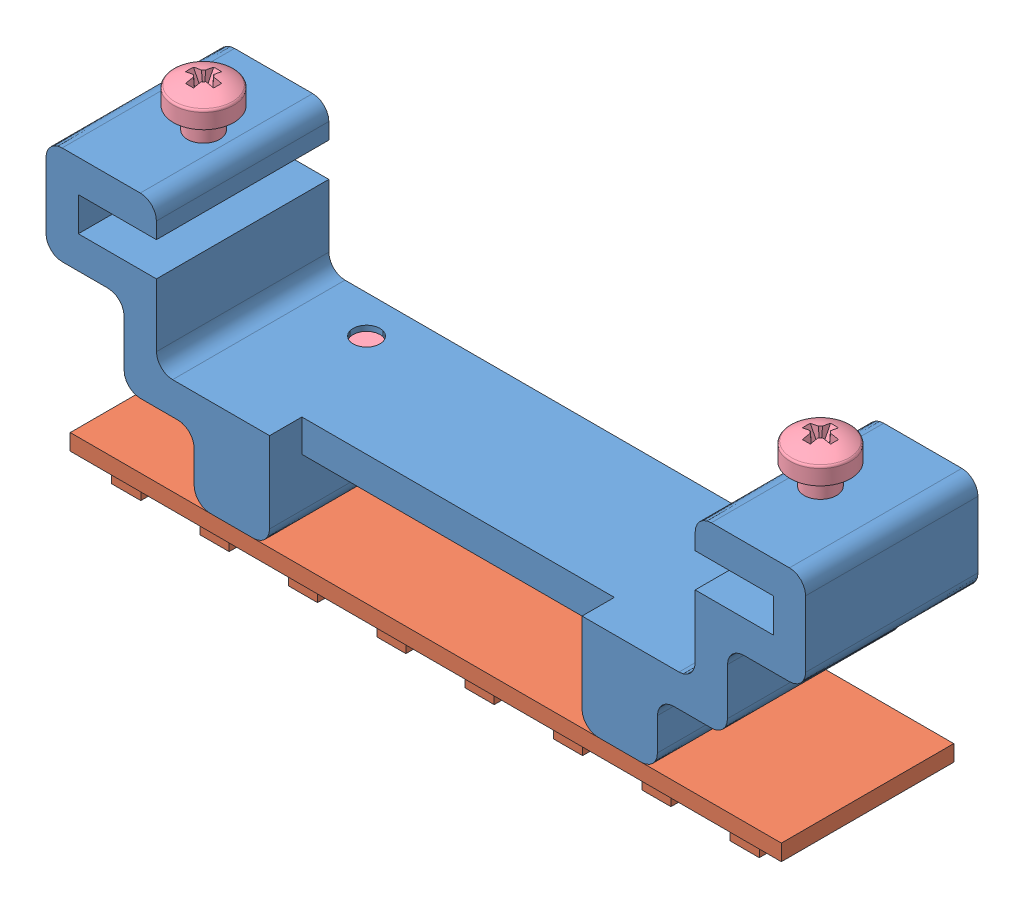
SolidWorks assembly Assembly schuiver QTR-8A, configuration Default. Lengths in mm.
Overall size (70.5 30.71 16).
7 component instances, 4 part files, 23 mates.
Components (placement in the parent):
- QTR-8A schuiver-1: QTR-8A schuiver [Default] at (0 0 -13.425) size (70.5 22.5 16)
- QTR-8A-1: QTR-8A [Default] at (0 -21 -5.425) x (1 0 0) z (0 0 -1) size (66 3.1 16)
- Header11P90-1: Header11P90 [Default] at (-12.7 -22.46 -12.155) x (0 0 1) z (0 1 0) size (8.45 27.94 7.3)
- pan head cross recess screw_iso-1: pan head cross recess screw_iso [ISO 7045 - M3 x 10 - Z - 10N] at (18 -23.4 -9.925) x (0 1 0) z (1 0 0) size (12.35 5.6 5.6)
- pan head cross recess screw_iso-2: pan head cross recess screw_iso [ISO 7045 - M3 x 10 - Z - 10N] at (-18 -23.4 -9.925) x (0 1 0) z (1 0 0) size (12.35 5.6 5.6)
- pan head cross recess screw_iso-3: pan head cross recess screw_iso [ISO 7045 - M3 x 5 - Z - 5N] at (-28.625 7.4 -5.425) x (0 -1 0) z (0 0 1) size (7.35 5.6 5.6)
- pan head cross recess screw_iso-4: pan head cross recess screw_iso [ISO 7045 - M3 x 5 - Z - 5N] at (28.625 7.4 -5.425) x (0 -1 0) z (0 0 1) size (7.35 5.6 5.6)
Mates (geometry in assembly coordinates):
- Coincident1: coincident aligned: plane of QTR-8A schuiver-1 through (0 0 -13.425) normal (1 0 0)
- Coincident3: coincident anti-aligned: plane of QTR-8A schuiver-1 through (21.5 -19.5 2.575) normal (0 -1 0); plane of QTR-8A-1 through (0 -19.5 -5.425) normal (0 1 0)
- Coincident4: coincident aligned: plane of QTR-8A schuiver-1 through (0 0 2.575) normal (0 0 1); plane of QTR-8A-1 through (-33 -19.5 2.575) normal (0 0 1)
- Coincident5: coincident aligned: plane of QTR-8A-1 through (0 -21 -5.425) normal (1 0 0)
- Coincident6: coincident: point of QTR-8A-1
- Coincident7: coincident aligned: plane of QTR-8A-1 through (-33 -19.5 -13.425) normal (0 0 -1); plane of Header11P90-1 through (13.97 -19.5 -13.425) normal (0 0 -1)
- Coincident8: coincident anti-aligned: plane of QTR-8A-1 through (0 -19.5 -5.425) normal (0 1 0); plane of Header11P90-1 through (11.43 -19.5 -12.925) normal (0 -1 0)
- Coincident9: coincident: unknown of Header11P90-1
- Coincident10: coincident aligned: plane of hex thin nut chamfered gradeab_iso-1 through (-19.5877 -21 -7.175) normal (0 1 0); plane of hex thin nut chamfered gradeab_iso-2 through (16.4123 -21 -7.175) normal (0 1 0)
- Concentric1: concentric anti-aligned: cylinder of QTR-8A-1 through (-18 -19.5 -9.925) axis (0 -1 0) radius 1.5; cylinder of hex thin nut chamfered gradeab_iso-1 through (-18 -22.8 -9.925) axis (0 1 0) radius 1.25
- Coincident11: coincident anti-aligned: plane of QTR-8A-1 through (0 -21 -5.425) normal (0 -1 0); plane of hex thin nut chamfered gradeab_iso-2 through (16.4123 -21 -7.175) normal (0 1 0)
- Concentric2: concentric aligned: cylinder of QTR-8A-1 through (18 -19.5 -9.925) axis (0 -1 0) radius 1.5; cylinder of hex thin nut chamfered gradeab_iso-2 through (18 -21 -9.925) axis (0 -1 0) radius 1.25
- Coincident12: coincident aligned: plane of hex thin nut chamfered gradeab_iso-1 through (-16.4123 -22.8 -12.675) normal (0 0 -1); plane of hex thin nut chamfered gradeab_iso-2 through (16.4123 -21 -12.675) normal (0 0 -1)
- Coincident13: coincident aligned: plane of pan head cross recess screw_iso-1 through (18 -21 -8.425) normal (0 1 0); plane of pan head cross recess screw_iso-2 through (-18 -21 -8.425) normal (0 1 0)
- Coincident14: coincident aligned: plane of pan head cross recess screw_iso-1 through (18.5275 -21.65 -9.555) normal (0 0 -1); plane of pan head cross recess screw_iso-2 through (-17.4725 -21.65 -9.555) normal (0 0 -1)
- Coincident15: coincident anti-aligned: plane of QTR-8A-1 through (0 -21 -5.425) normal (0 -1 0); plane of pan head cross recess screw_iso-2 through (-18 -21 -8.425) normal (0 1 0)
- Concentric3: concentric aligned: cylinder of QTR-8A-1 through (-18 -19.5 -9.925) axis (0 -1 0) radius 1.5; cylinder of pan head cross recess screw_iso-2 through (-18 -48.8 -9.925) axis (0 -1 0) radius 1.5
- Concentric4: concentric aligned: cylinder of QTR-8A-1 through (18 -19.5 -9.925) axis (0 -1 0) radius 1.5; cylinder of pan head cross recess screw_iso-1 through (18 -48.8 -9.925) axis (0 -1 0) radius 1.5
- Coincident16: coincident aligned: plane of pan head cross recess screw_iso-3 through (-27.125 0 -5.425) normal (0 -1 0); plane of pan head cross recess screw_iso-4 through (30.125 0 -5.425) normal (0 -1 0)
- Coincident17: coincident aligned: plane of QTR-8A schuiver-1 through (-25 0 2.575) normal (0 -1 0); plane of pan head cross recess screw_iso-3 through (-27.125 0 -5.425) normal (0 -1 0)
- Concentric5: concentric aligned: cylinder of QTR-8A schuiver-1 through (-28.625 -19.501 -5.425) axis (0 1 0) radius 1.25; cylinder of pan head cross recess screw_iso-3 through (-28.625 32.8 -5.425) axis (0 1 0) radius 1.5
- Concentric6: concentric aligned: cylinder of QTR-8A schuiver-1 through (28.625 -19.501 -5.425) axis (0 1 0) radius 1.25; cylinder of pan head cross recess screw_iso-4 through (28.625 32.8 -5.425) axis (0 1 0) radius 1.5
- Coincident18: coincident aligned: plane of pan head cross recess screw_iso-3 through (-28.0975 5.65 -5.795) normal (0 0 1); plane of pan head cross recess screw_iso-4 through (29.1525 5.65 -5.795) normal (0 0 1)
